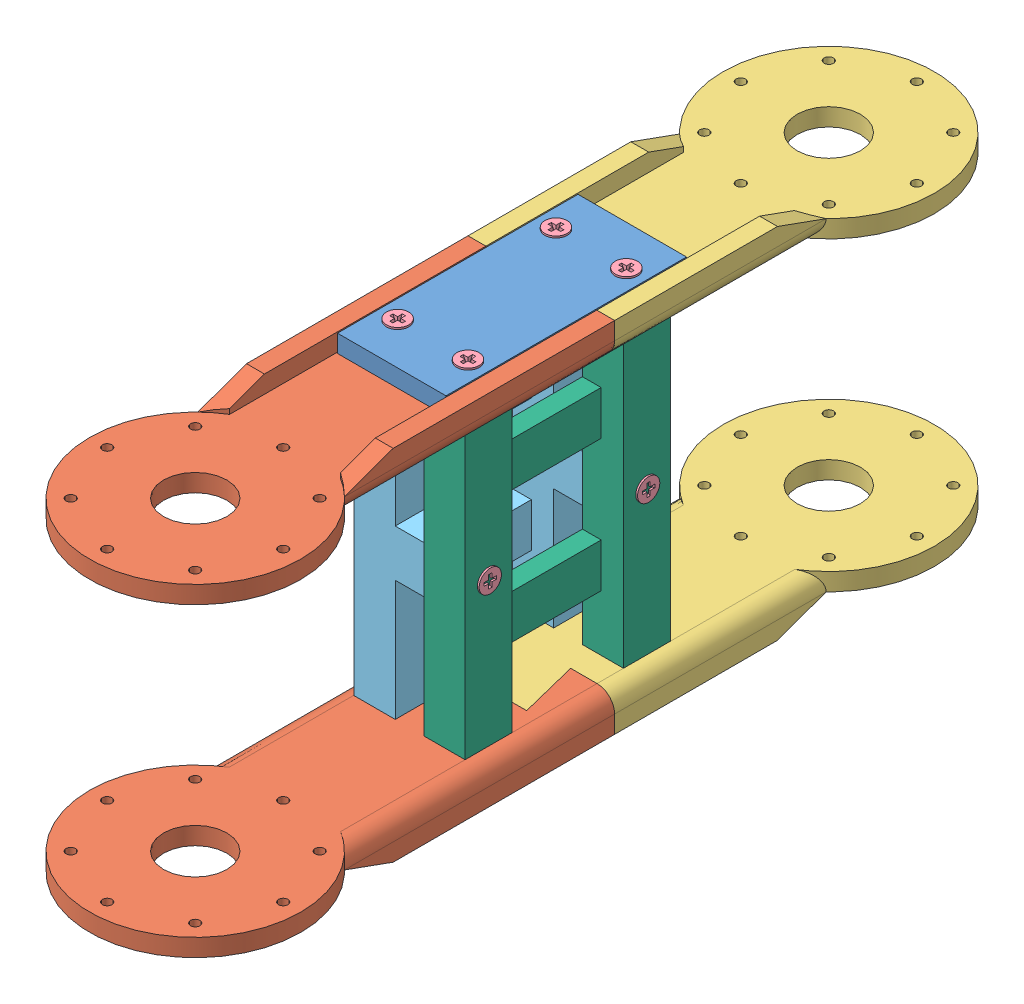
SolidWorks assembly Ensamblaje-Eslabon2, configuration Predeterminado. Lengths in mm.
Overall size (35.99 61.7 144).
20 component instances, 6 part files, 13 mates.
Components (placement in the parent):
- Ensamblaje-Eslabon2AB-1: Ensamblaje-Eslabon2AB [Predeterminado] at origin size (35.99 13 144)
  - Agarre-Eslabon2AyB-1: Agarre-Eslabon2AyB [Predeterminado] at (-14.421 1.0451 41) size (18.5 3 41)
  - Eslabon2A-1: Eslabon2A [Predeterminado] at (-11.6524 -1.9549 75.4017) x (1 0 0) z (0 0 1) size (35.99 6 77)
  - Eslabon2B-1: Eslabon2B [Predeterminado] at (-11.1985 -1.9549 7.7213) x (-1 0 0) z (0 0 -1) size (35.99 6 77)
  - flat head screw_am-2: flat head screw_am [B18.6.7M - M2 x 0.4 x 13 Type I Cross Recessed FHMS --13S] at (-5.4254 4.3451 55.0617) x (0 -1 0) z (0.013375 0 0.999911) size (13 3.8 3.8)
  - flat head screw_am-3: flat head screw_am [B18.6.7M - M2 x 0.4 x 13 Type I Cross Recessed FHMS --13S] at (-17.425 4.3451 55.0617) x (0 -1 0) z (0 0 1) size (13 3.8 3.8)
  - flat head screw_am-4: flat head screw_am [B18.6.7M - M2 x 0.4 x 13 Type I Cross Recessed FHMS --13S] at (-17.4254 4.3451 28.0617) x (0 -1 0) z (0 0 1) size (13 3.8 3.8)
  - flat head screw_am-5: flat head screw_am [B18.6.7M - M2 x 0.4 x 13 Type I Cross Recessed FHMS --13S] at (-5.4254 4.3451 28.0617) x (0 -1 0) z (0 0 1) size (13 3.8 3.8)
- Ensamblaje-Eslabon2AB-2: Ensamblaje-Eslabon2AB [Predeterminado] at (-22.8505 -53.0099 -0.0004) x (-1 0 0) z (0 0 1) size (35.99 13 144)
  - Agarre-Eslabon2AyB-1: Agarre-Eslabon2AyB [Predeterminado] at (-14.421 1.0451 41) size (18.5 3 41)
  - Eslabon2A-1: Eslabon2A [Predeterminado] at (-11.6524 -1.9549 75.4017) x (1 0 0) z (0 0 1) size (35.99 6 77)
  - Eslabon2B-1: Eslabon2B [Predeterminado] at (-11.1985 -1.9549 7.7213) x (-1 0 0) z (0 0 -1) size (35.99 6 77)
  - flat head screw_am-2: flat head screw_am [B18.6.7M - M2 x 0.4 x 13 Type I Cross Recessed FHMS --13S] at (-5.4254 4.3451 55.0617) x (0 -1 0) z (0.013375 0 0.999911) size (13 3.8 3.8)
  - flat head screw_am-3: flat head screw_am [B18.6.7M - M2 x 0.4 x 13 Type I Cross Recessed FHMS --13S] at (-17.425 4.3451 55.0617) x (0 -1 0) z (0 0 1) size (13 3.8 3.8)
  - flat head screw_am-4: flat head screw_am [B18.6.7M - M2 x 0.4 x 13 Type I Cross Recessed FHMS --13S] at (-17.4254 4.3451 28.0617) x (0 -1 0) z (0 0 1) size (13 3.8 3.8)
  - flat head screw_am-5: flat head screw_am [B18.6.7M - M2 x 0.4 x 13 Type I Cross Recessed FHMS --13S] at (-5.4254 4.3451 28.0617) x (0 -1 0) z (0 0 1) size (13 3.8 3.8)
- Conexion-Eslabones2-1: Conexion-Eslabones2 [Predeterminado] at (-20.8254 -26.6184 42.469) x (0 0 1) z (0 1 0) size (35 11.9 49.1)
- Conexion-Eslabones22-1: Conexion-Eslabones22 [Predeterminado] at (-8.9254 -26.6184 42.469) x (0 0 1) z (0 1 0) size (35 7 49.1)
- flat head screw_am-2: flat head screw_am [B18.6.7M - M2 x 0.4 x 13 Type I Cross Recessed FHMS --13S] at (-1.6254 -26.5049 55.0614) x (-1 0 0) z (0 0 -1) size (13 3.8 3.8)
- flat head screw_am-3: flat head screw_am [B18.6.7M - M2 x 0.4 x 13 Type I Cross Recessed FHMS --13S] at (-1.6254 -26.5049 28.0614) x (-1 0 0) z (0 0 -1) size (13 3.8 3.8)
Mates (geometry in assembly coordinates):
- Coincidente1: coincident: plane of Conexion-Eslabones2-1 through (-13.8254 -1.9549 51.0614) normal (0 1 0); plane of Conexion-Eslabones22-1 through (-1.9254 -1.9549 51.0614) normal (0 1 0)
- Coincidente2: coincident: plane of Conexion-Eslabones2-1 through (-13.8254 -1.9549 59.0614) normal (0 0 1); plane of Conexion-Eslabones22-1 through (-1.9254 -1.9549 59.0614) normal (0 0 1)
- Coincidente3: coincident: plane of Conexion-Eslabones2-1 through (-8.9254 -26.6184 42.469) normal (1 0 0); plane of Conexion-Eslabones22-1 through (-8.9254 -26.6184 42.469) normal (-1 0 0)
- Coincidente4: coincident: axis of Ensamblaje-Eslabon2AB-1/Eslabon2A-1 through (-5.4254 1.0451 55.0614) axis (0 -1 0); axis of Conexion-Eslabones22-1 through (-5.4254 -51.0549 55.0614) axis (0 1 0)
- Paralelo1: parallel: line of Conexion-Eslabones2-1 through (-20.8254 -1.9549 24.0614) axis (0 0 1); line of Ensamblaje-Eslabon2AB-1/Eslabon2B-1 through (-20.9254 -1.9549 36.5614) axis (0 0 -1)
- Coincidente6: coincident: plane of Ensamblaje-Eslabon2AB-1/Eslabon2A-1 through (-11.4254 -1.9549 95.565) normal (0 -1 0); plane of Conexion-Eslabones22-1 through (-1.9254 -1.9549 51.0614) normal (0 1 0)
- Coincidente7: coincident: plane of Ensamblaje-Eslabon2AB-2/Eslabon2A-1 through (-11.425 -51.0549 95.5646) normal (0 1 0); plane of Conexion-Eslabones22-1 through (-1.9254 -51.0549 59.0614) normal (0 -1 0)
- Coincidente8: coincident: axis of Ensamblaje-Eslabon2AB-2/flat head screw_am-3 through (-5.4254 -55.2036 55.0614) axis (0 -1 0); axis of Conexion-Eslabones22-1 through (-5.4254 -51.0549 55.0614) axis (0 1 0)
- Paralelo2: parallel: line of Ensamblaje-Eslabon2AB-2/Eslabon2B-1 through (-20.925 -51.0549 2.8424) axis (0 0 1); line of Conexion-Eslabones2-1 through (-20.8254 -51.0549 32.0614) axis (0 0 -1)
- Concéntrica1: concentric: cylinder of Conexion-Eslabones2-1 through (-8.9254 -26.5049 55.0614) axis (-1 0 0) radius 1; cone of flat head screw_am-2 through (-1.9254 -26.5049 55.0614) axis (-1 0 0)
- Concéntrica2: concentric: cylinder of Conexion-Eslabones2-1 through (-8.9254 -26.5049 28.0614) axis (-1 0 0) radius 1; cone of flat head screw_am-3 through (-1.9254 -26.5049 28.0614) axis (-1 0 0)
- Coincidente10: coincident: plane of flat head screw_am-2 through (-1.6254 -26.5049 55.0614) normal (1 0 0); plane of flat head screw_am-3 through (-1.6254 -26.5049 28.0614) normal (1 0 0)
- Coincidente11: coincident: plane of Conexion-Eslabones22-1 through (-1.9254 -26.6184 42.469) normal (1 0 0); circle of flat head screw_am-3
